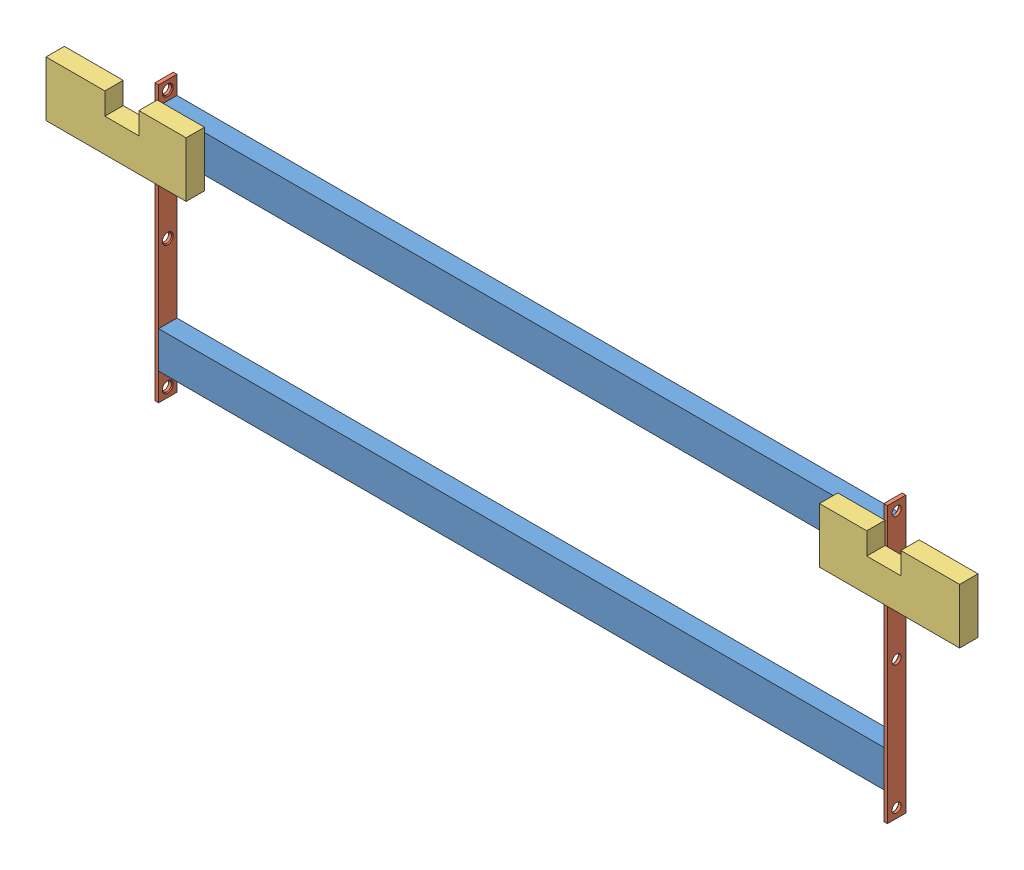
SolidWorks assembly ПерекладинаСб, configuration По умолчанию. Lengths in mm.
Overall size (995.3 300 40).
6 component instances, 3 part files, 12 mates.
Components (placement in the parent):
- Перекладина-1: Перекладина [По умолчанию] at (792 260 0) x (0 0 -1) z (0 1 0) size (20 790 40)
- ПланкаКОЗ-1: ПланкаКОЗ [По умолчанию] at origin size (4 300 20)
- Перекладина-2: Перекладина [По умолчанию] at (792 50 0) x (0 0 -1) z (0 1 0) size (20 790 40)
- ПланкаКОЗ-3: ПланкаКОЗ [По умолчанию] at (794 0 0) x (-1 0 0) z (0 0 -1) size (4 300 20)
- ПрокладкаКЗ-1: ПрокладкаКЗ [По умолчанию] at (-100.6507 225 10) size (152.65 60.04 20)
- ПрокладкаКЗ-2: ПрокладкаКЗ [По умолчанию] at (894.6507 225 30) x (-1 0 0) z (0 0 -1) size (152.65 60.04 20)
Mates (geometry in assembly coordinates):
- Совпадение3: coincident anti-aligned: plane of Перекладина-1 through (2 260 0) normal (-1 0 0); plane of ПланкаКОЗ-1 through (2 300 -10) normal (1 0 0)
- Расстояние1: distance = 20 mm aligned: plane of Перекладина-1 through (2 280 10) normal (0 1 0); plane of ПланкаКОЗ-1 through (0 300 0) normal (0 1 0)
- Совпадение5: coincident aligned: plane of Перекладина-1 through (2 240 10) normal (0 0 1); plane of ПланкаКОЗ-1 through (-2 300 10) normal (0 0 1)
- Совпадение7: coincident anti-aligned: plane of Перекладина-1 through (792 260 0) normal (1 0 0); plane of ПланкаКОЗ-3 through (792 300 10) normal (-1 0 0)
- Совпадение8: coincident aligned: plane of ПланкаКОЗ-1 through (0 300 0) normal (0 1 0); plane of ПланкаКОЗ-3 through (794 300 0) normal (0 1 0)
- Совпадение9: coincident aligned: plane of ПланкаКОЗ-1 through (-2 300 10) normal (0 0 1); plane of ПланкаКОЗ-3 through (796 300 10) normal (0 0 1)
- Совпадение10: coincident anti-aligned: plane of Перекладина-1 through (2 240 10) normal (0 0 1); plane of ПрокладкаКЗ-1 through (-100.6507 225 10) normal (0 0 -1)
- Расстояние2: distance = 15 mm aligned: plane of Перекладина-1 through (2 240 10) normal (0 -1 0); plane of ПрокладкаКЗ-1 through (-100.6507 225 30) normal (0 -1 0)
- Расстояние3: distance = 50 mm aligned: plane of ПрокладкаКЗ-1 through (52 225 30) normal (1 0 0); plane of ПланкаКОЗ-1 through (2 300 -10) normal (1 0 0)
- Совпадение13: coincident: plane of Перекладина-1 through (2 240 10) normal (0 0 1); plane of ПрокладкаКЗ-2 through (894.6507 225 10) normal (0 0 -1)
- Расстояние4: distance = 50 mm: plane of ПланкаКОЗ-3 through (792 300 10) normal (-1 0 0); plane of ПрокладкаКЗ-2 through (742 225 10) normal (-1 0 0)
- Совпадение15: coincident aligned: plane of ПрокладкаКЗ-1 through (-100.6507 225 30) normal (0 -1 0); plane of ПрокладкаКЗ-2 through (894.6507 225 10) normal (0 -1 0)
